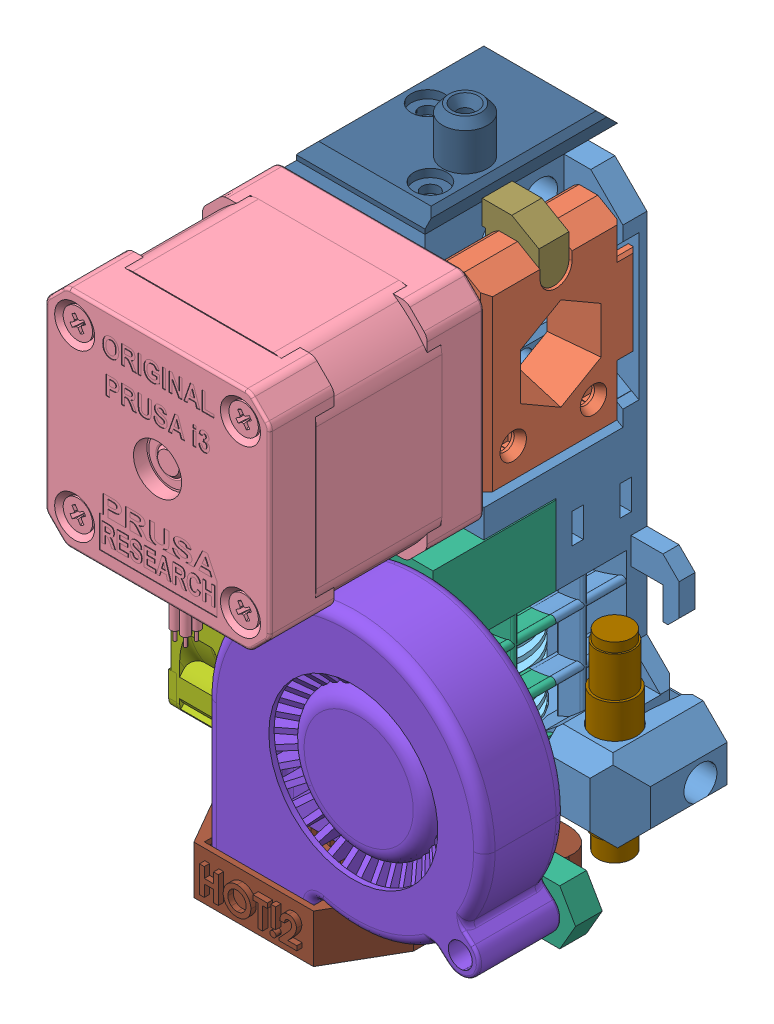
SolidWorks assembly Extruder Assembly, configuration Default. Lengths in mm.
Overall size (76.41 114.5 76).
12 component instances, 12 part files, 31 mates.
Components (placement in the parent):
- extruder-body(R2)-1: extruder-body(R2) [Default] at (14.2402 58.6454 60.8767) x (-1 0 0) z (0 0 -1) size (63.5 95 30.5)
- extruder-idler(R2)-1: extruder-idler(R2) [Default] at (14.2402 58.6454 59.3767) x (0 0 1) z (-1 0 0) size (28 34 17)
- idler pulley shaft-1: idler pulley shaft [Default] at (18.2402 85.6454 62.1267) size (3 3 24)
- NEMA-17 40mm PR-1: NEMA-17 40mm PR [По умолчанию] at (10.2402 85.6454 131.3767) x (-1 0 0) z (0 -1 0) size (42.3 62 51.35)
- E3D V6-1: E3D V6 [Default] at (14.2402 48.5454 77.8767) x (1 0 0) z (0 -1 0) size (21.69 25.84 58.6)
- extruder-cover(R2)-1: extruder-cover(R2) [Default] at (14.2402 58.6454 60.8767) x (-1 0 0) z (0 0 -1) size (75.15 49.75 23.94)
- Noctua-NF-A4x10-1: Noctua-NF-A4x10 [Default] at (-12.2589 37.0799 80.8112) x (0 -1 0) z (-1 0 0) size (40.06 40.06 12.26)
- FAN_5015_BLOWER-1: FAN_5015_BLOWER [Default] at (31.7402 38.1454 116.2767) x (0 -1 0) z (1 0 0) size (51.75 17.19 52.1)
- PINDA Probe-1: PINDA Probe [Default] at (37.2402 32.9116 72.8767) x (1 0 0) z (0 -1 0) size (7.8 7.8 35.75)
- filament-sensor-cover-1: filament-sensor-cover [Default] at (14.2402 58.6454 60.8767) x (-1 0 0) z (0 0 -1) size (24 11.5 36)
- nozzle-fan-1: nozzle-fan [Default] at (14.2402 58.6454 65.3767) x (-1 0 0) z (0 0 -1) size (47.83 17 42)
- extruder-idler-plug-1: extruder-idler-plug [Default] at (13.8402 58.6454 59.3767) x (-1 0 0) z (0 0 -1) size (10.6 10.3 5.6)
Mates (geometry in assembly coordinates):
- Concentric1: concentric aligned: cylinder of extruder-idler(R2)-1 through (18.2402 85.6454 91.3767) axis (0 0 -1) radius 1.45; cylinder of idler pulley shaft-1 through (18.2402 85.6454 86.1267) axis (0 0 -1) radius 1.5
- Coincident1: coincident aligned: plane of extruder-idler(R2)-1 through (7.2402 85.6454 86.1267) normal (0 0 1); plane of idler pulley shaft-1 through (18.2402 85.6454 86.1267) normal (0 0 1)
- Coincident2: coincident anti-aligned: circle of extruder-body(R2)-1; cylinder of extruder-idler(R2)-1 through (25.7402 101.1454 91.3767) axis (0 0 -1) radius 1.65
- Coincident3: coincident aligned: plane of extruder-body(R2)-1 through (14.2402 58.6454 78.3767) normal (0 0 1); plane of extruder-idler(R2)-1 through (14.2402 58.6454 78.3767) normal (0 0 1)
- Coincident4: coincident anti-aligned: plane of extruder-body(R2)-1 through (31.2402 22.1454 91.3767) normal (0 0 1); plane of NEMA-17 40mm PR-1 through (10.2402 85.6454 91.3767) normal (0 0 -1)
- Concentric2: concentric anti-aligned: cylinder of extruder-body(R2)-1 through (-5.2598 101.1454 100.8767) axis (0 0 -1) radius 1.65; circle of NEMA-17 40mm PR-1
- Concentric3: concentric anti-aligned: circle of extruder-body(R2)-1; circle of NEMA-17 40mm PR-1
- Concentric4: concentric aligned: cylinder of extruder-body(R2)-1 through (14.2402 62.6454 77.8767) axis (0 -1 0) radius 6.05; cylinder of E3D V6-1 through (14.2402 48.5454 77.8767) axis (0 -1 0) radius 5.95
- Coincident5: coincident anti-aligned: plane of extruder-body(R2)-1 through (14.2402 55.2454 77.8767) normal (0 -1 0); plane of E3D V6-1 through (6.3402 55.2454 77.8767) normal (0 1 0)
- Parallel1: parallel aligned: plane of extruder-body(R2)-1 through (-6.2598 56.1454 85.8767) normal (-1 0 0); plane of E3D V6-1 through (6.7402 8.3454 82.8767) normal (-1 0 0)
- Coincident6: coincident anti-aligned: plane of extruder-body(R2)-1 through (32.2402 19.6454 77.8767) normal (0 0 1); plane of extruder-cover(R2)-1 through (31.2402 22.1454 77.8767) normal (0 0 -1)
- Coincident7: coincident anti-aligned: circle of extruder-body(R2)-1; cylinder of extruder-cover(R2)-1 through (25.7402 58.1454 103.8767) axis (0 0 -1) radius 1.65
- Concentric5: concentric aligned: cylinder of extruder-body(R2)-1 through (-2.7598 61.6454 85.8767) axis (0 0 -1) radius 1.7; cylinder of extruder-cover(R2)-1 through (-2.7598 61.6454 104.8767) axis (0 0 -1) radius 1.6
- Coincident8: coincident anti-aligned: plane of extruder-body(R2)-1 through (-6.2598 56.1454 85.8767) normal (-1 0 0); plane of Noctua-NF-A4x10-1 through (-6.2598 55.1078 98.8391) normal (1 0 0)
- Concentric6: concentric anti-aligned: circle of extruder-cover(R2)-1; cylinder of Noctua-NF-A4x10-1 through (-17.758 53.1454 96.8767) axis (1 0 0) radius 2.159
- Parallel2: parallel aligned: plane of extruder-cover(R2)-1 through (31.2402 22.1454 100.8767) normal (0 0 1); plane of Noctua-NF-A4x10-1 through (-17.758 55.1078 100.8391) normal (0 0 1)
- Coincident10: coincident anti-aligned: plane of extruder-cover(R2)-1 through (31.2402 22.1454 100.8767) normal (0 0 1); plane of FAN_5015_BLOWER-1 through (31.7402 38.1454 100.8767) normal (0 0 -1)
- Concentric10: concentric anti-aligned: circle of extruder-cover(R2)-1; cylinder of FAN_5015_BLOWER-1 through (8.7402 58.1454 116.2767) axis (0 0 -1) radius 2.25
- Parallel3: parallel aligned: plane of extruder-cover(R2)-1 through (-1.2598 14.6454 100.8767) normal (0 -1 0); plane of FAN_5015_BLOWER-1 through (24.3402 12.4454 116.2767) normal (0 -1 0)
- Concentric13: concentric anti-aligned: cylinder of extruder-body(R2)-1 through (37.2402 53.6454 72.8767) axis (0 -1 0) radius 4.05; cylinder of PINDA Probe-1 through (37.2402 46.9306 72.8767) axis (0 1 0) radius 3.9
- Coincident11: coincident aligned: plane of E3D V6-1 through (14.2402 8.3454 77.8767) normal (0 -1 0); plane of PINDA Probe-1 through (37.2402 8.3454 72.8767) normal (0 -1 0)
- Coincident12: coincident anti-aligned: plane of extruder-body(R2)-1 through (31.2402 108.6454 91.3767) normal (0 1 0); plane of filament-sensor-cover-1 through (20.2402 108.6454 91.3767) normal (0 -1 0)
- Concentric14: concentric aligned: cone of extruder-body(R2)-1 through (15.2402 108.6454 85.3767) axis (0 -1 0); cylinder of filament-sensor-cover-1 through (15.2402 113.1454 85.3767) axis (0 -1 0) radius 3.1
- Concentric15: concentric aligned: cone of extruder-body(R2)-1 through (2.2402 108.6454 72.8767) axis (0 -1 0); cylinder of filament-sensor-cover-1 through (2.2402 118.6454 72.8767) axis (0 -1 0) radius 1.6
- Coincident13: coincident anti-aligned: plane of extruder-cover(R2)-1 through (31.2402 22.1454 100.8767) normal (0 0 1); plane of nozzle-fan-1 through (3.7402 5.6454 100.8767) normal (0 0 -1)
- Concentric16: concentric anti-aligned: cylinder of extruder-cover(R2)-1 through (-0.2598 18.1454 102.8767) axis (0 0 -1) radius 1.4; circle of nozzle-fan-1
- Parallel4: parallel anti-aligned: plane of extruder-cover(R2)-1 through (-1.2598 14.6454 100.8767) normal (0 -1 0); plane of nozzle-fan-1 through (3.7402 22.6454 105.8767) normal (0 1 0)
- Concentric18: concentric: cylinder of extruder-idler(R2)-1 through (34.2402 101.6454 77.8767) axis (-1 0 0) radius 3; cylinder of extruder-idler-plug-1 through (41.5613 101.6454 77.8767) axis (-1 0 0) radius 2.8
- Parallel5: parallel: plane of extruder-body(R2)-1 through (31.2402 22.1454 91.3767) normal (1 0 0); plane of extruder-idler-plug-1 through (41.5613 101.6454 80.6767) normal (1 0 0)
- Parallel6: parallel: plane of extruder-body(R2)-1 through (31.2402 22.1454 60.8767) normal (0 0 -1); plane of extruder-idler-plug-1 through (41.5613 101.6454 75.0767) normal (0 0 -1)
- Coincident15: coincident anti-aligned: plane of extruder-body(R2)-1 through (20.2402 87.6454 97.3767) normal (1 0 0); plane of extruder-idler-plug-1 through (20.2402 104.6454 80.6767) normal (-1 0 0)
